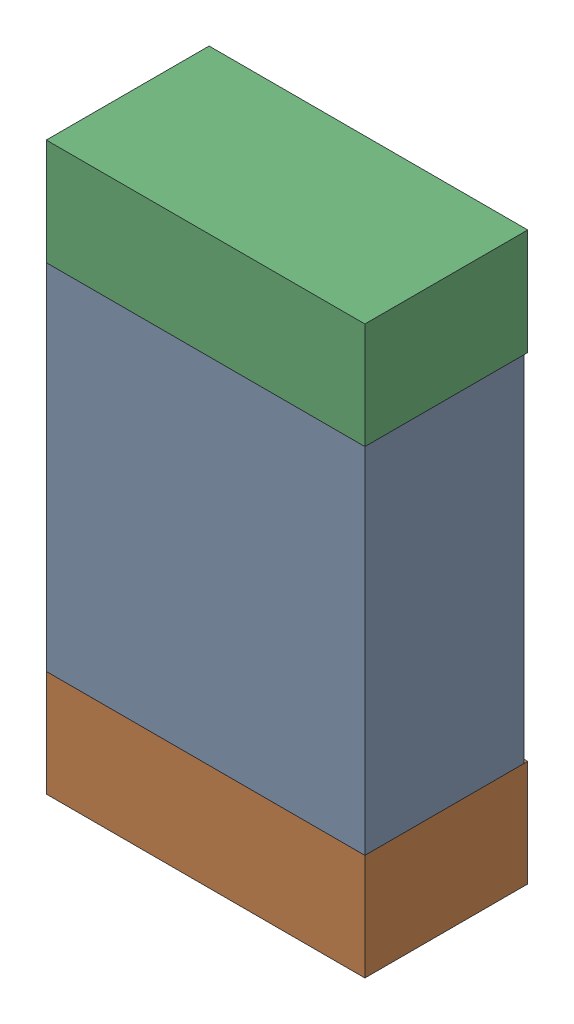
SolidWorks assembly L5, configuration Default. Lengths in mm.
Overall size (0.9 1.6 0.46).
6 component instances, 2 part files, 0 mates.
Components (placement in the parent):
- 870944160-1: 870944160 [Default] at (41.071 40.587 -2.0506) size (0.9 1 0.45)
  - Extruded_25-1: Extruded_25 [Default] at origin size (0.9 1 0.45)
- 870944320-1: 870944320 [Default] at (41.071 39.937 -2.0606) size (0.9 0.3 0.46)
  - Extruded_26-1: Extruded_26 [Default] at origin size (0.9 0.3 0.46)
- 870944320-2: 870944320 [Default] at (41.071 41.237 -2.0606) size (0.9 0.3 0.46)
  - Extruded_26-1: Extruded_26 [Default] at origin size (0.9 0.3 0.46)
